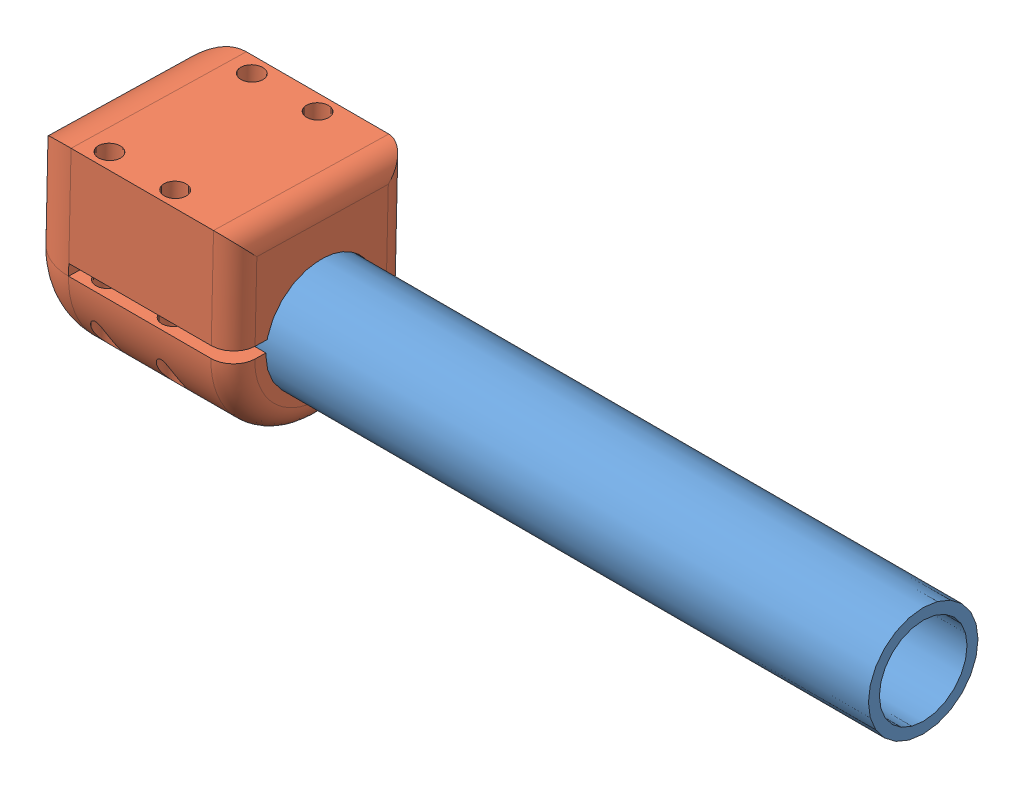
SolidWorks assembly bicopter_v1, configuration Défaut. Lengths in mm.
Overall size (75 18.36 16.41).
2 component instances, 2 part files, 1 mates.
Components (placement in the parent):
- axe-1: axe [Défaut] at (-22.3534 3.417 70) size (70 10 10)
- enboutAxe-1: enboutAxe [Défaut] at (-7.3534 3.417 70) x (0 0.022999 0.999735) z (0 -0.999735 0.022999) size (16 20 18)
Mates (geometry in assembly coordinates):
- Coïncidente2: coincident anti-aligned: circle of axe-1; circle of enboutAxe-1
